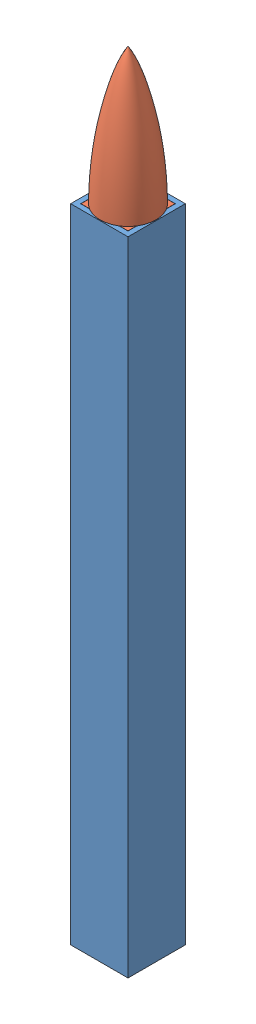
SolidWorks assembly Assem1, configuration Default. Lengths in mm.
Overall size (18.9 256.5 18.9).
2 component instances, 2 part files, 3 mates.
Components (placement in the parent):
- LightSaberBladeCut-1: LightSaberBladeCut [Default] at (79.5837 -0.2668 165.3301) size (18.9 211.5 18.9)
- LightSaberBladeTipForCut-1: LightSaberBladeTipForCut [Default] at (79.5837 196.2332 165.3301) size (18.4 60 18.4)
Mates (geometry in assembly coordinates):
- Distance1: distance = 0.05 mm anti-aligned: plane of LightSaberBladeTipForCut-1 through (71.8337 211.2332 173.0801) normal (0 0 1); plane of LightSaberBladeCut-1 through (71.7837 211.2332 173.1301) normal (0 0 -1)
- Distance2: distance = 0.05 mm anti-aligned: plane of LightSaberBladeCut-1 through (87.3837 211.2332 173.1301) normal (-1 0 0); plane of LightSaberBladeTipForCut-1 through (87.3337 211.2332 173.0801) normal (1 0 0)
- Coincident3: coincident aligned: plane of LightSaberBladeCut-1 through (79.5837 211.2332 165.3301) normal (0 1 0); circle of LightSaberBladeTipForCut-1
